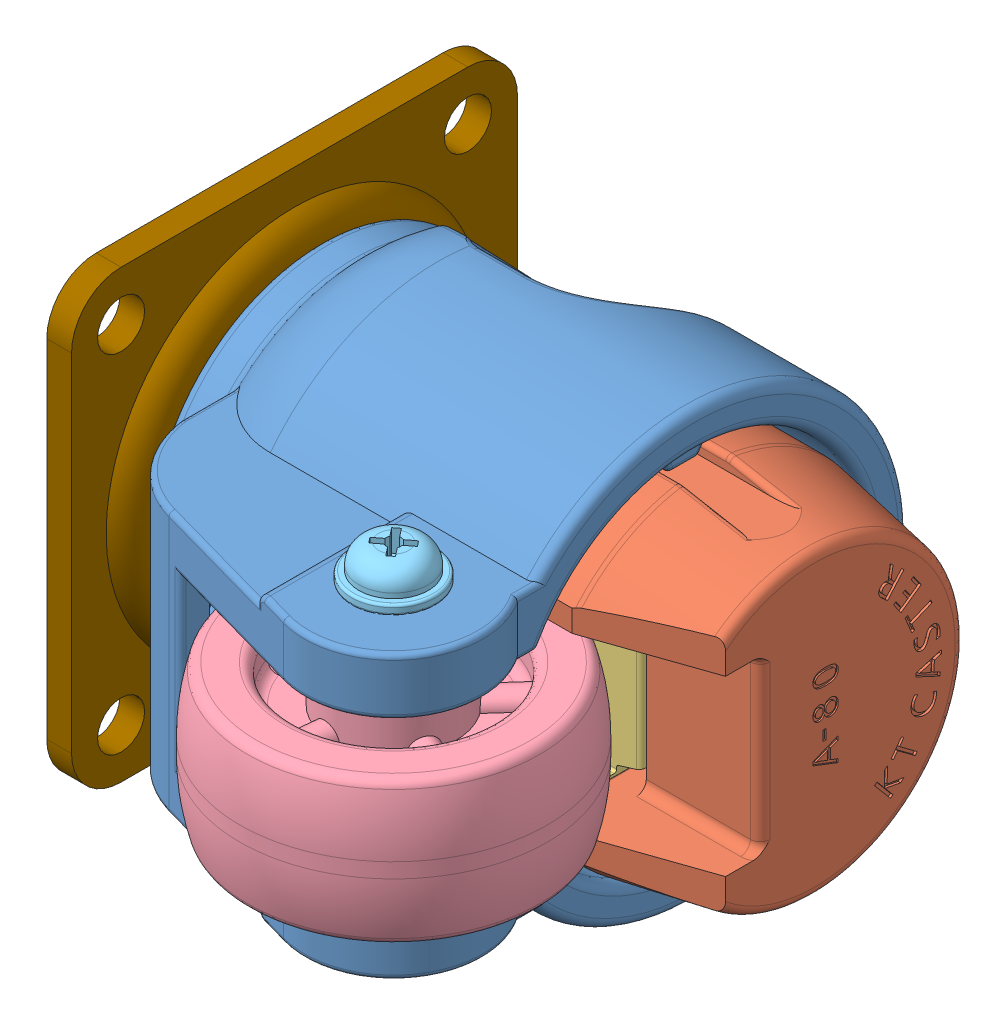
SolidWorks assembly Колесо в сборе, configuration По умолчанию. Lengths in mm.
Overall size (114.27 90 122).
10 component instances, 10 part files, 18 mates.
Components (placement in the parent):
- Корпус-1: Корпус [默认] at (12.6757 69.7097 68.4528) size (79.29 86.01 107.16)
- Пятка-1: Пятка [默认] at (12.6757 69.7097 68.4528) size (46 67.23 61.03)
- Основание пятки-1: Основание пятки [默认] at (12.6757 69.7097 68.4528) size (20.01 61.04 50.03)
- Колесо-1: Колесо [默认] at (12.6757 70.2097 68.4528) size (62 32 62)
- Болт боковой-1: Болт боковой [默认] at (14.4098 69.7097 66.7817) x (0.999315 0 0.037014) z (-0.037014 0 0.999315) size (17 17 17)
- Болт боковой 2-1: Болт боковой 2 [默认] at (12.6757 69.7097 68.4528) size (17 63.04 17)
- Ось-1: Ось [默认] at (12.6757 69.7097 68.4528) size (72.4 38 38)
- Кольца-1: Кольца [默认] at (12.6757 69.7097 68.4528) x (1 0 0) z (0 0.493898 0.86952) size (32 26 26)
- Планка-1: Планка [默认] at (12.6757 69.7097 68.4528) size (37.27 90 90)
- Регулятор-1: Регулятор [默认] at (12.6757 69.7097 68.4528) size (13.51 61.89 61.89)
Mates (geometry in assembly coordinates):
- Концентричный1: concentric aligned: circle of Корпус-1; circle of Пятка-1
- Расстояние1: distance = 24 mm aligned: plane of Корпус-1 through (73.6757 108.9597 68.4528) normal (1 0 0); plane of Пятка-1 through (97.6757 84.7097 68.4528) normal (1 0 0)
- Совпадение2: coincident aligned: plane of Пятка-1 through (53.6757 101.2097 68.4528) normal (-1 0 0); plane of Основание пятки-1 through (53.6757 55.4597 68.4528) normal (-1 0 0)
- Концентричный2: concentric anti-aligned: circle of Пятка-1; circle of Основание пятки-1
- Концентричный3: concentric aligned: circle of Корпус-1; circle of Колесо-1
- Расстояние2: distance = 1 mm anti-aligned: plane of Корпус-1 through (82.8636 52.7097 68.4528) normal (0 1 0); plane of Колесо-1 through (67.9242 53.7097 115.4299) normal (0 -1 0)
- Концентричный4: concentric anti-aligned: circle of Корпус-1; circle of Болт боковой-1
- Совпадение4: coincident anti-aligned: plane of Корпус-1 through (59.4714 98.2097 113.7241) normal (0 1 0); plane of Болт боковой-1 through (58.6757 98.2097 114.4528) normal (0 -1 0)
- Концентричный5: concentric anti-aligned: circle of Корпус-1; circle of Болт боковой 2-1
- Совпадение5: coincident anti-aligned: plane of Корпус-1 through (59.4714 41.2097 113.7241) normal (0 -1 0); plane of Болт боковой 2-1 through (58.6757 41.2097 114.4528) normal (0 1 0)
- Расстояние3: distance = 21 mm aligned: plane of Пятка-1 through (97.6757 84.7097 68.4528) normal (1 0 0); plane of Ось-1 through (76.6757 69.7097 68.4528) normal (1 0 0)
- Концентричный6: concentric aligned: circle of Основание пятки-1; circle of Ось-1
- Концентричный7: concentric anti-aligned: circle of Основание пятки-1; circle of Кольца-1
- Расстояние4: distance = 9 mm aligned: plane of Корпус-1 through (-2.3243 101.9457 68.4528) normal (-1 0 0); plane of Кольца-1 through (-11.3243 69.7097 68.4528) normal (-1 0 0)
- Концентричный8: concentric aligned: circle of Кольца-1; circle of Планка-1
- Расстояние5: distance = 1 mm aligned: plane of Кольца-1 through (-11.3243 69.7097 68.4528) normal (-1 0 0); plane of Планка-1 through (-12.3243 69.7097 27.9528) normal (-1 0 0)
- Расстояние6: distance = 24 mm aligned: plane of Корпус-1 through (-2.3243 101.9457 68.4528) normal (-1 0 0); plane of Регулятор-1 through (21.6757 70.494 56.1027) normal (-1 0 0)
- Концентричный9: concentric aligned: circle of Основание пятки-1; circle of Регулятор-1
